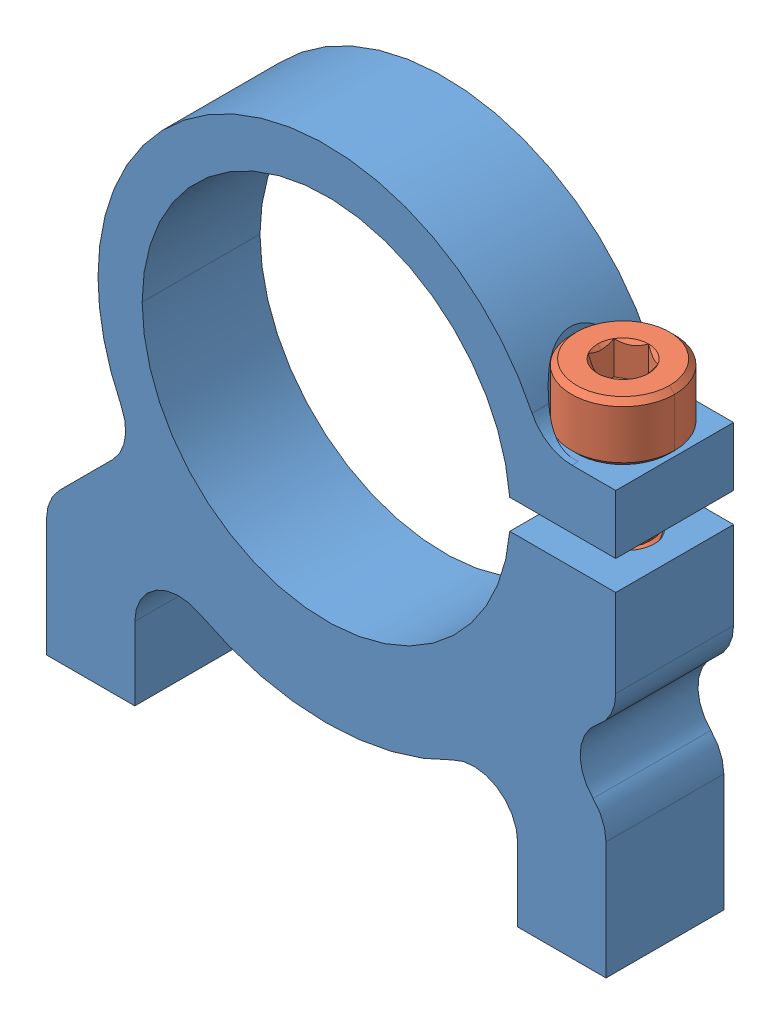
SolidWorks assembly 1400-0032-0025 assembly, configuration Default. Lengths in mm.
Overall size (38.66 39.51 8).
3 component instances, 2 part files, 0 mates.
Components (placement in the parent):
- 1400-0032-0025 assembly.STEP-1: 1400-0032-0025 assembly.STEP [Default] at origin size (38.66 39.51 8)
  - 1400-0032-0025.STEP-1: 1400-0032-0025.STEP [Default] at (-36.3751 25.389 0.7434) size (38.66 39.51 8)
  - 2800-0004-0010_90128A207.STEP-1: 2800-0004-0010_90128A207.STEP [Default] at (-20.2151 20.389 4.7434) x (1 0 0) z (0 -1 0) size (7 7 14.01)
